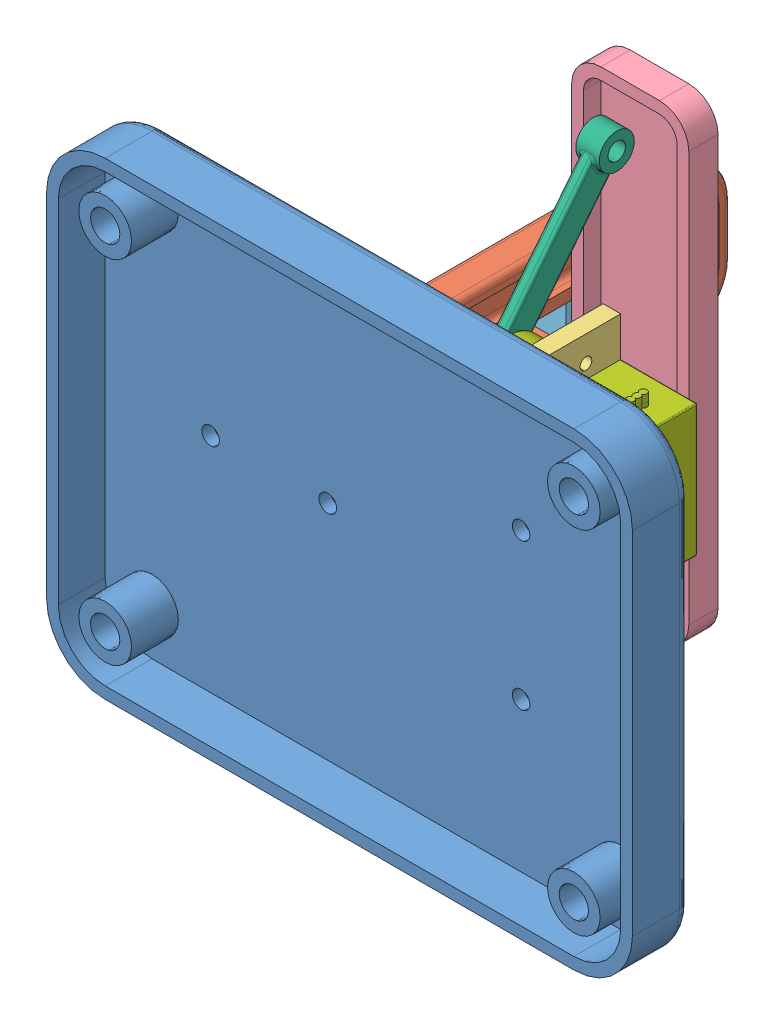
SolidWorks assembly motion study assembly, configuration Default. Lengths in mm.
Overall size (100 80 83).
7 component instances, 7 part files, 16 mates.
Components (placement in the parent):
- base-1: base [Default] at (47.3616 44.5592 71.6448) size (100 80 10)
- bracket-1: bracket [Default] at (28.1599 44.5592 71.6448) x (-1 0 0) z (0 0 -1) size (36 36 73)
- servo mount-1: servo mount [Default] at (52.3616 44.5592 68.6448) x (1 0 0) z (0 1 0) size (33 33 36)
- shelf-2: shelf [Default] at (41.1599 44.5592 20.8198) size (26 80 5)
- clip-1: clip [Default] at (23.1599 44.5592 23.3198) x (0 -1 0) z (1 0 0) size (10 7 8)
- servo arm-1: servo arm [Default] at (36.8616 61.5631 35.2425) x (0 -0.783147 0.621837) z (0 -0.621837 -0.783147) size (38.16 4 10)
- Micro Servo FS90R Continuous-1: Micro Servo FS90R Continuous [Valor predeterminado] at (49.3616 44.5592 44.5754) x (0 -1 0) z (0 0 -1) size (32 29 12)
Mates (geometry in assembly coordinates):
- Parallel1: parallel anti-aligned: plane of base-1 through (47.3616 44.5592 71.6448) normal (0 0 1); plane of bracket-1 through (28.1599 44.5592 71.6448) normal (0 0 -1)
- Coincident9: coincident anti-aligned: circle of base-1; circle of bracket-1
- Coincident10: coincident anti-aligned: circle of base-1; circle of bracket-1
- Coincident11: coincident anti-aligned: circle of servo mount-1; circle of base-1
- Coincident12: coincident anti-aligned: circle of base-1; circle of servo mount-1
- Coincident16: coincident anti-aligned: plane of servo mount-1 through (49.3616 55.8092 50.6448) normal (0 -1 0); plane of Micro Servo FS90R Continuous-1 through (65.3616 55.8092 50.5754) normal (0 1 0)
- Coincident17: coincident aligned: circle of servo mount-1; cylinder of Micro Servo FS90R Continuous-1 through (47.3616 30.9342 44.5754) axis (1 0 0) radius 1
- Coincident18: coincident anti-aligned: plane of servo mount-1 through (49.3616 62.5592 68.6448) normal (-1 0 0); plane of Micro Servo FS90R Continuous-1 through (49.3616 58.1842 44.5754) normal (1 0 0)
- Concentric2: concentric anti-aligned: cylinder of servo arm-1 through (38.8616 49.8092 44.5754) axis (-1 0 0) radius 2.25; cylinder of Micro Servo FS90R Continuous-1 through (36.3616 49.8092 44.5754) axis (1 0 0) radius 2.25
- Coincident26: coincident anti-aligned: plane of bracket-1 through (25.1599 32.0592 -1.3552) normal (-1 0 0); plane of clip-1 through (25.1599 44.5592 23.3198) normal (1 0 0)
- Coincident27: coincident anti-aligned: plane of bracket-1 through (-12.8401 47.5592 46.6448) normal (0 -1 0); plane of clip-1 through (31.1599 47.5592 19.8198) normal (0 1 0)
- Coincident29: coincident anti-aligned: circle of shelf-2; circle of clip-1
- Coincident30: coincident anti-aligned: plane of shelf-2 through (41.1599 44.5592 25.8198) normal (0 0 1); plane of clip-1 through (31.1599 47.5592 25.8198) normal (0 0 -1)
- Concentric1: concentric anti-aligned: circle of servo arm-1; cylinder of Micro Servo FS90R Continuous-1 through (36.3616 49.8092 44.5754) axis (1 0 0) radius 2.25
- Distance3: distance = 1 mm anti-aligned: plane of servo arm-1 through (37.8616 49.8092 44.5754) normal (1 0 0); plane of Micro Servo FS90R Continuous-1 through (38.8616 49.8092 44.5754) normal (-1 0 0)
- Parallel3: parallel anti-aligned: plane of servo arm-1 through (37.8616 49.8092 44.5754) normal (1 0 0); plane of Micro Servo FS90R Continuous-1 through (38.8616 49.8092 44.5754) normal (-1 0 0)
